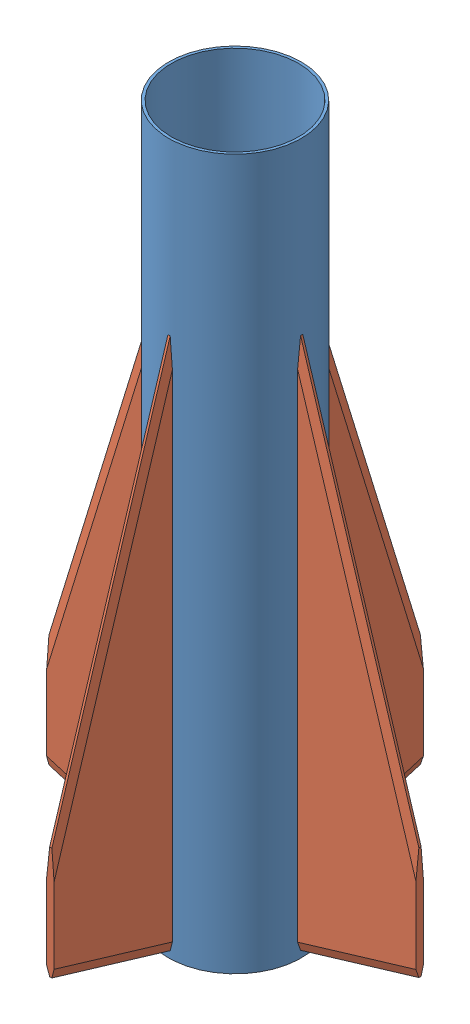
SolidWorks assembly Fin Can Assembly, configuration Default. Lengths in mm.
Overall size (158.55 304.8 158.55).
5 component instances, 2 part files, 3 mates.
Components (placement in the parent):
- Body Tube-1: Body Tube [Fin Can] at origin size (56.95 304.8 56.95)
- Fin-1: Fin [Default] at (1.5875 231.648 28.4734) x (0 -1 0) z (0 0 -1) size (228.6 3.17 50.8)
- Fin-2: Fin [Default] at (-28.4734 231.648 1.5875) x (0 -1 0) z (1 0 0) size (228.6 3.17 50.8)
- Fin-3: Fin [Default] at (-1.5875 231.648 -28.4734) x (0 -1 0) z (0 0 1) size (228.6 3.17 50.8)
- Fin-4: Fin [Default] at (28.4734 231.648 -1.5875) x (0 -1 0) z (-1 0 0) size (228.6 3.17 50.8)
Mates (geometry in assembly coordinates):
- Width1: width: plane of assembly; plane of assembly; plane of assembly; plane of assembly; plane of Fin-1 through (1.5875 231.648 28.4734) normal (1 0 0); plane of Fin-1 through (-1.5875 231.648 28.4734) normal (-1 0 0)
- Tangent1: tangent anti-aligned: cylinder of Body Tube-1 through (0 304.8 0) axis (0 -1 0) radius 28.4734; plane of Fin-1 through (-1.5875 231.648 28.4734) normal (0 0 -1)
- Distance1: distance = 3.048 mm: line of Fin-1 through (-0.3175 3.048 28.4734) axis (1 0 0); plane of Body Tube-1 through (0 0 0) normal (0 -1 0)
